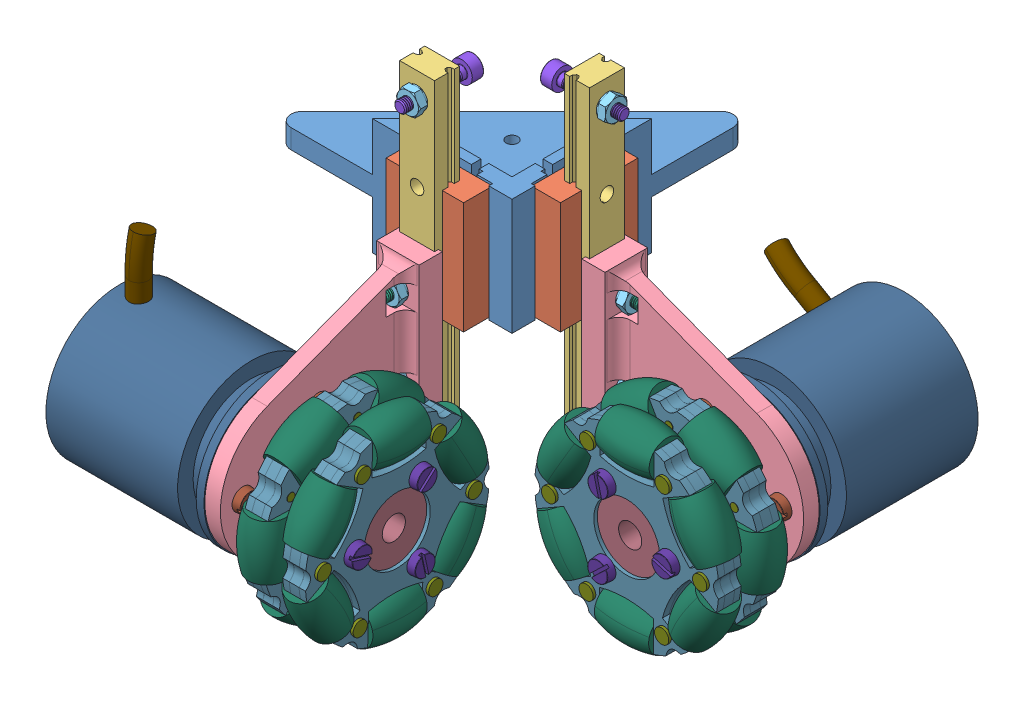
SolidWorks assembly 全场定位, configuration 默认. Lengths in mm.
Overall size (134 104.66 134.28).
113 component instances, 18 part files, 0 mates.
Components (placement in the parent):
- 机架SLDPRT-1: 机架SLDPRT [默认] at (33.577 -2.0729 87.0624) size (60.04 30 60.04)
- 滑块-1: 滑块 [默认] at (40.077 -14.0229 81.0624) x (0 1 0) z (0 0 1) size (28.9 7.5 20)
- 滑块-2: 滑块 [默认] at (7.577 -14.0229 93.5624) x (0 1 0) z (-1 0 0) size (28.9 7.5 20)
- 滑轨-1: 滑轨 [默认] at (17.577 -49.5817 95.5624) size (9 90 6.5)
- 滑轨-2: 滑轨 [默认] at (42.077 -51.1888 71.0624) x (0 0 -1) z (1 0 0) size (9 90 6.5)
- 连接片-1: 连接片 [默认] at (19.577 -30.8137 129.5624) x (0 0 1) z (0 -1 0) size (53.77 11 52.42)
- 连接片-2: 连接片 [默认] at (76.077 -32.4209 69.0624) x (1 0 0) z (0 -1 0) size (53.77 11 52.42)
- hex nut style 1 gradeab_iso_ISO - 4032 - M3 - W - N-1: hex nut style 1 gradeab_iso_ISO - 4032 - M3 - W - N [默认] at (17.577 -45.5817 102.9624) x (-0.883653 0.468143 0) z (0 0 1) size (5.5 6.35 2.4)
- socket head cap screw_iso_ISO 4762 M3 x 12 - 12S-1: socket head cap screw_iso_ISO 4762 M3 x 12 - 12S [默认] at (17.577 -25.5817 89.5624) x (0 0 1) z (0.159835 -0.987144 0) size (15 5.5 5.5)
- socket head cap screw_iso_ISO 4762 M3 x 12 - 12S-2: socket head cap screw_iso_ISO 4762 M3 x 12 - 12S [默认] at (17.577 -5.5817 89.5624) x (0 0 1) z (0.284229 -0.958757 0) size (15 5.5 5.5)
- socket head cap screw_iso_ISO 4762 M3 x 12 - 12S-3: socket head cap screw_iso_ISO 4762 M3 x 12 - 12S [默认] at (36.077 -27.1888 71.0624) x (1 0 0) z (0 -0.834413 -0.551139) size (15 5.5 5.5)
- socket head cap screw_iso_ISO 4762 M3 x 12 - 12S-4: socket head cap screw_iso_ISO 4762 M3 x 12 - 12S [默认] at (36.077 -7.1888 71.0624) x (1 0 0) z (0 -0.855064 -0.518522) size (15 5.5 5.5)
- hex nut style 1 gradeab_iso_ISO - 4032 - M3 - W - N-2: hex nut style 1 gradeab_iso_ISO - 4032 - M3 - W - N [默认] at (17.577 -25.5817 102.9624) x (0 -1 0) z (0 0 1) size (5.5 6.35 2.4)
- hex nut style 1 gradeab_iso_ISO - 4032 - M3 - W - N-3: hex nut style 1 gradeab_iso_ISO - 4032 - M3 - W - N [默认] at (17.577 -5.5817 102.9624) x (0 -1 0) z (0 0 1) size (5.5 6.35 2.4)
- hex nut style 1 gradeab_iso_ISO - 4032 - M3 - W - N-4: hex nut style 1 gradeab_iso_ISO - 4032 - M3 - W - N [默认] at (49.477 -7.1888 71.0624) x (0 0.5 -0.866025) z (1 0 0) size (5.5 6.35 2.4)
- hex nut style 1 gradeab_iso_ISO - 4032 - M3 - W - N-5: hex nut style 1 gradeab_iso_ISO - 4032 - M3 - W - N [默认] at (49.477 -27.1888 71.0624) x (0 0.5 -0.866025) z (1 0 0) size (5.5 6.35 2.4)
- hex nut style 1 gradeab_iso_ISO - 4032 - M3 - W - N-6: hex nut style 1 gradeab_iso_ISO - 4032 - M3 - W - N [默认] at (49.477 -47.1888 71.0624) x (0 0.5 -0.866025) z (1 0 0) size (5.5 6.35 2.4)
- socket set screw cone point_iso_ISO 4027 - M4 x 4-N-1: socket set screw cone point_iso_ISO 4027 - M4 x 4-N [默认] at (27.077 -24.3164 129.375) x (0 -0.999584 0.028835) z (0.266634 -0.027791 -0.963397) size (4 4 4)
- socket set screw cone point_iso_ISO 4027 - M4 x 4-N-2: socket set screw cone point_iso_ISO 4027 - M4 x 4-N [默认] at (70.4593 -29.151 80.5624) x (0.864249 -0.503064 0) z (0.099801 0.171456 -0.980124) size (4 4 4)
- socket head cap screw_iso_ISO 4762 M3 x 16 - 16S-1: socket head cap screw_iso_ISO 4762 M3 x 16 - 16S [默认] at (32.577 -47.1888 71.0624) x (1 0 0) z (0 -0.325683 0.945479) size (19 5.5 5.5)
- hex nut style 1 gradeab_iso_ISO - 4032 - M3 - W - N-7: hex nut style 1 gradeab_iso_ISO - 4032 - M3 - W - N [默认] at (36.677 -47.1888 71.0624) x (0 -0.95795 0.286936) z (-1 0 0) size (5.5 6.35 2.4)
- hex nut style 1 gradeab_iso_ISO - 4032 - M3 - W - N-8: hex nut style 1 gradeab_iso_ISO - 4032 - M3 - W - N [默认] at (17.577 -45.5817 90.1624) x (-0.5 0.866025 0) z (0 0 -1) size (5.5 6.35 2.4)
- socket head cap screw_iso_ISO 4762 M3 x 16 - 16S-2: socket head cap screw_iso_ISO 4762 M3 x 16 - 16S [默认] at (17.577 -45.5817 86.0624) x (0 0 1) z (-0.77707 -0.629414 0) size (19 5.5 5.5)
- socket head cap screw_iso_ISO 4762 M3 x 6 - 6S-1: socket head cap screw_iso_ISO 4762 M3 x 6 - 6S [默认] at (23.577 5.4271 63.5624) x (1 0 0) z (0 0.484775 0.874639) size (9 5.5 5.5)
- socket head cap screw_iso_ISO 4762 M3 x 6 - 6S-2: socket head cap screw_iso_ISO 4762 M3 x 6 - 6S [默认] at (25.577 5.4271 78.5624) x (1 0 0) z (0 0.339966 0.940438) size (9 5.5 5.5)
- socket head cap screw_iso_ISO 4762 M3 x 6 - 6S-3: socket head cap screw_iso_ISO 4762 M3 x 6 - 6S [默认] at (25.577 -4.5729 63.5624) x (1 0 0) z (0 0.125522 0.992091) size (9 5.5 5.5)
- socket head cap screw_iso_ISO 4762 M3 x 6 - 6S-4: socket head cap screw_iso_ISO 4762 M3 x 6 - 6S [默认] at (10.077 5.4271 77.0624) x (0 0 1) z (-0.629289 -0.777171 0) size (9 5.5 5.5)
- socket head cap screw_iso_ISO 4762 M3 x 6 - 6S-5: socket head cap screw_iso_ISO 4762 M3 x 6 - 6S [默认] at (10.077 -4.5729 79.0624) x (0 0 1) z (-0.32553 -0.945532 0) size (9 5.5 5.5)
- socket head cap screw_iso_ISO 4762 M3 x 6 - 6S-6: socket head cap screw_iso_ISO 4762 M3 x 6 - 6S [默认] at (25.077 -4.5729 79.0624) x (0 0 1) z (0.017492 -0.999847 0) size (9 5.5 5.5)
- hex nut style 1 gradeab_iso_ISO - 4032 - M3 - W - N-9: hex nut style 1 gradeab_iso_ISO - 4032 - M3 - W - N [默认] at (17.577 34.4183 97.9624) x (-0.846539 -0.532326 0) z (0 0 1) size (5.5 6.35 2.4)
- hex nut style 1 gradeab_iso_ISO - 4032 - M3 - W - N-10: hex nut style 1 gradeab_iso_ISO - 4032 - M3 - W - N [默认] at (17.577 34.4183 90.1624) x (0.675882 -0.73701 0) z (0 0 -1) size (5.5 6.35 2.4)
- hex nut style 1 gradeab_iso_ISO - 4032 - M3 - W - N-11: hex nut style 1 gradeab_iso_ISO - 4032 - M3 - W - N [默认] at (36.677 32.8112 71.0624) x (0 -0.87174 0.489968) z (-1 0 0) size (5.5 6.35 2.4)
- hex nut style 1 gradeab_iso_ISO - 4032 - M3 - W - N-12: hex nut style 1 gradeab_iso_ISO - 4032 - M3 - W - N [默认] at (44.477 32.8112 71.0624) x (0 0.818224 -0.574899) z (1 0 0) size (5.5 6.35 2.4)
- socket head cap screw_iso_ISO 4762 M3 x 16 - 16S-3: socket head cap screw_iso_ISO 4762 M3 x 16 - 16S [默认] at (17.577 34.4183 81.0624) x (0 0 1) z (-0.514934 -0.85723 0) size (19 5.5 5.5)
- socket head cap screw_iso_ISO 4762 M3 x 16 - 16S-4: socket head cap screw_iso_ISO 4762 M3 x 16 - 16S [默认] at (27.577 32.8112 71.0624) x (1 0 0) z (0 -0.968527 0.248907) size (19 5.5 5.5)
- 编码器1-1: 编码器1 [默认] at (-25.223 -30.8137 129.5624) x (0 0 1) z (0 1 0) size (38 40.8 38)
- 编码器1-2: 编码器1 [默认] at (76.077 -32.4209 28.2624) x (-0.5 -0.866025 0) z (-0.866025 0.5 0) size (38 40.8 38)
- slotted cheese head screw_iso_ISO 1207 - M3 x 8 - 8N-1: slotted cheese head screw_iso_ISO 1207 - M3 x 8 - 8N [默认] at (89.077 -32.4209 75.0624) x (0 0 -1) z (1 0 0) size (10.01 8.61 5.5)
- slotted cheese head screw_iso_ISO 1207 - M3 x 8 - 8N-2: slotted cheese head screw_iso_ISO 1207 - M3 x 8 - 8N [默认] at (69.577 -21.1626 75.0624) x (0 0 -1) z (-0.5 0.866025 0) size (10.01 8.61 5.5)
- slotted cheese head screw_iso_ISO 1207 - M3 x 8 - 8N-3: slotted cheese head screw_iso_ISO 1207 - M3 x 8 - 8N [默认] at (69.577 -43.6792 75.0624) x (0 0 -1) z (-0.5 -0.866025 0) size (10.01 8.61 5.5)
- slotted cheese head screw_iso_ISO 1207 - M3 x 8 - 8N-4: slotted cheese head screw_iso_ISO 1207 - M3 x 8 - 8N [默认] at (21.577 -30.8137 142.5624) x (-1 0 0) z (0 0.285358 -0.958421) size (10.01 8.61 5.5)
- slotted cheese head screw_iso_ISO 1207 - M3 x 8 - 8N-5: slotted cheese head screw_iso_ISO 1207 - M3 x 8 - 8N [默认] at (21.577 -42.0721 123.0624) x (-1 0 0) z (0 0.687338 0.726338) size (10.01 8.61 5.5)
- slotted cheese head screw_iso_ISO 1207 - M3 x 8 - 8N-6: slotted cheese head screw_iso_ISO 1207 - M3 x 8 - 8N [默认] at (21.577 -19.5554 123.0624) x (-1 0 0) z (0 -0.972696 0.232083) size (10.01 8.61 5.5)
- 轴-1: 轴 [默认] at (10.577 -30.8137 129.5624) x (0 0.028835 0.999584) z (0 0.999584 -0.028835) size (6 25 6)
- 轴-2: 轴 [默认] at (76.077 -32.4209 64.0624) x (-0.503064 -0.864249 0) z (-0.864249 0.503064 0) size (6 25 6)
- 法兰（新）-1: 法兰（新） [默认] at (40.577 -30.8137 129.5624) x (0 0.999584 -0.028835) z (0 0.028835 0.999584) size (28 22 28)
- 2mm全向轮片1-1: 2mm全向轮片1 [默认] at (35.577 -30.8137 129.5624) x (0 -0.474821 0.880083) z (-1 0 0) size (47.34 45.39 5.9)
- 从动-1: 从动 [默认] at (27.0518 -30.4732 129.7462) x (0 -0.474821 0.880083) z (-0.964226 0.233294 0.125866) size (14 11.67 11.67)
- 从动-2: 从动 [默认] at (27.0518 -30.8026 129.9492) x (0 -0.999584 0.028835) z (-0.964226 0.007644 0.264972) size (14 11.67 11.67)
- 从动-3: 从动 [默认] at (27.0518 -31.1431 129.7655) x (0 -0.524764 -0.851248) z (-0.964226 -0.225651 0.139106) size (14 11.67 11.67)
- 从动-4: 从动 [默认] at (27.0518 -31.1542 129.3787) x (0 0.474821 -0.880083) z (-0.964226 -0.233294 -0.125866) size (14 11.67 11.67)
- 从动-5: 从动 [默认] at (27.0518 -30.8249 129.1757) x (0 0.999584 -0.028835) z (-0.964226 -0.007644 -0.264972) size (14 11.67 11.67)
- 从动-6: 从动 [默认] at (27.0518 -30.4844 129.3594) x (0 0.524764 0.851248) z (-0.964226 0.225651 -0.139106) size (14 11.67 11.67)
- 2mm全向轮片1-2: 2mm全向轮片1 [默认] at (46.477 -30.8137 129.5624) x (0 -0.851248 0.524764) z (-1 0 0) size (47.34 45.39 5.9)
- 从动-7: 从动 [默认] at (37.9518 -30.6107 129.8918) x (0 -0.851248 0.524764) z (-0.964226 0.139106 0.225651) size (14 11.67 11.67)
- 从动-8: 从动 [默认] at (37.9518 -30.9974 129.903) x (0 -0.880083 -0.474821) z (-0.964226 -0.125866 0.233294) size (14 11.67 11.67)
- 从动-9: 从动 [默认] at (37.9518 -31.2005 129.5736) x (0 -0.028835 -0.999584) z (-0.964226 -0.264972 0.007644) size (14 11.67 11.67)
- 从动-10: 从动 [默认] at (37.9518 -31.0168 129.2331) x (0 0.851248 -0.524764) z (-0.964226 -0.139106 -0.225651) size (14 11.67 11.67)
- 从动-11: 从动 [默认] at (37.9518 -30.63 129.2219) x (0 0.880083 0.474821) z (-0.964226 0.125866 -0.233294) size (14 11.67 11.67)
- 从动-12: 从动 [默认] at (37.9518 -30.427 129.5513) x (0 0.028835 0.999584) z (-0.964226 0.264972 -0.007644) size (14 11.67 11.67)
- thin head rivets gb_GB_CONNECTING_PIECE_RIVET_THR 2X6-1: thin head rivets gb_GB_CONNECTING_PIECE_RIVET_THR 2X6 [默认] at (47.157 -14.2144 119.3296) x (-1 0 0) z (0 -0.996106 -0.088163) size (6.68 3.74 3.74)
- thin head rivets gb_GB_CONNECTING_PIECE_RIVET_THR 2X6-2: thin head rivets gb_GB_CONNECTING_PIECE_RIVET_THR 2X6 [默认] at (47.157 -13.6521 138.8214) x (-1 0 0) z (0 -0.421702 -0.906735) size (6.68 3.74 3.74)
- thin head rivets gb_GB_CONNECTING_PIECE_RIVET_THR 2X6-3: thin head rivets gb_GB_CONNECTING_PIECE_RIVET_THR 2X6 [默认] at (47.157 -30.2515 149.0543) x (-1 0 0) z (0 0.574404 -0.818572) size (6.68 3.74 3.74)
- thin head rivets gb_GB_CONNECTING_PIECE_RIVET_THR 2X6-4: thin head rivets gb_GB_CONNECTING_PIECE_RIVET_THR 2X6 [默认] at (47.157 -47.4131 139.7953) x (-1 0 0) z (0 0.996106 0.088163) size (6.68 3.74 3.74)
- thin head rivets gb_GB_CONNECTING_PIECE_RIVET_THR 2X6-5: thin head rivets gb_GB_CONNECTING_PIECE_RIVET_THR 2X6 [默认] at (47.157 -47.9753 120.3034) x (-1 0 0) z (0 0.421702 0.906735) size (6.68 3.74 3.74)
- thin head rivets gb_GB_CONNECTING_PIECE_RIVET_THR 2X6-6: thin head rivets gb_GB_CONNECTING_PIECE_RIVET_THR 2X6 [默认] at (47.157 -31.376 110.0706) x (-1 0 0) z (0 -0.574404 0.818572) size (6.68 3.74 3.74)
- thin head rivets gb_GB_CONNECTING_PIECE_RIVET_THR 2X6-7: thin head rivets gb_GB_CONNECTING_PIECE_RIVET_THR 2X6 [默认] at (28.997 -50.3056 130.1247) x (1 0 0) z (0 -0.812515 -0.582941) size (6.68 3.74 3.74)
- thin head rivets gb_GB_CONNECTING_PIECE_RIVET_THR 2X6-8: thin head rivets gb_GB_CONNECTING_PIECE_RIVET_THR 2X6 [默认] at (28.997 -41.0466 112.9631) x (1 0 0) z (0 0.098584 -0.995129) size (6.68 3.74 3.74)
- thin head rivets gb_GB_CONNECTING_PIECE_RIVET_THR 2X6-9: thin head rivets gb_GB_CONNECTING_PIECE_RIVET_THR 2X6 [默认] at (28.997 -21.5547 112.4008) x (1 0 0) z (0 0.911099 -0.412188) size (6.68 3.74 3.74)
- thin head rivets gb_GB_CONNECTING_PIECE_RIVET_THR 2X6-10: thin head rivets gb_GB_CONNECTING_PIECE_RIVET_THR 2X6 [默认] at (28.997 -11.3218 129.0002) x (1 0 0) z (0 0.812515 0.582941) size (6.68 3.74 3.74)
- thin head rivets gb_GB_CONNECTING_PIECE_RIVET_THR 2X6-11: thin head rivets gb_GB_CONNECTING_PIECE_RIVET_THR 2X6 [默认] at (28.997 -20.5808 146.1618) x (1 0 0) z (0 -0.098584 0.995129) size (6.68 3.74 3.74)
- thin head rivets gb_GB_CONNECTING_PIECE_RIVET_THR 2X6-12: thin head rivets gb_GB_CONNECTING_PIECE_RIVET_THR 2X6 [默认] at (28.997 -40.0727 146.7241) x (1 0 0) z (0 -0.911099 0.412188) size (6.68 3.74 3.74)
- slotted cheese head screw_iso_ISO 1207 - M3 x 10 - 10N-1: slotted cheese head screw_iso_ISO 1207 - M3 x 10 - 10N [默认] at (27.677 -25.5907 119.8815) x (1 0 0) z (0 0.028835 0.999584) size (12.01 8.61 5.5)
- slotted cheese head screw_iso_ISO 1207 - M3 x 10 - 10N-2: slotted cheese head screw_iso_ISO 1207 - M3 x 10 - 10N [默认] at (27.677 -25.0413 138.9262) x (1 0 0) z (0 -0.880083 -0.474821) size (12.01 8.61 5.5)
- slotted cheese head screw_iso_ISO 1207 - M3 x 10 - 10N-3: slotted cheese head screw_iso_ISO 1207 - M3 x 10 - 10N [默认] at (27.677 -41.8092 129.8796) x (1 0 0) z (0 0.851248 -0.524764) size (12.01 8.61 5.5)
- slotted cheese head screw_iso_ISO 1207 - M3 x 10 - 10N-4: slotted cheese head screw_iso_ISO 1207 - M3 x 10 - 10N [默认] at (48.477 -21.45 123.79) x (-1 0 0) z (0 0.673889 -0.738833) size (12.01 8.61 5.5)
- slotted cheese head screw_iso_ISO 1207 - M3 x 10 - 10N-5: slotted cheese head screw_iso_ISO 1207 - M3 x 10 - 10N [默认] at (48.477 -30.4965 140.5579) x (-1 0 0) z (0 0.302904 0.953021) size (12.01 8.61 5.5)
- slotted cheese head screw_iso_ISO 1207 - M3 x 10 - 10N-6: slotted cheese head screw_iso_ISO 1207 - M3 x 10 - 10N [默认] at (48.477 -40.4946 124.3394) x (-1 0 0) z (0 -0.976792 -0.214188) size (12.01 8.61 5.5)
- 法兰（新）-2: 法兰（新） [默认] at (76.077 -32.4209 94.0624) x (-0.864249 0.503064 0) z (-0.503064 -0.864249 0) size (28 22 28)
- 2mm全向轮片1-3: 2mm全向轮片1 [默认] at (76.077 -32.4209 89.0624) x (-0.003541 -0.999994 0) z (0 0 -1) size (47.34 45.39 5.9)
- 从动-13: 从动 [默认] at (75.69 -32.4195 80.5373) x (-0.003541 -0.999994 0) z (-0.265081 0.000939 -0.964226) size (14 11.67 11.67)
- 从动-14: 从动 [默认] at (75.8823 -32.7553 80.5373) x (0.864249 -0.503064 0) z (-0.133353 -0.229097 -0.964226) size (14 11.67 11.67)
- 从动-15: 从动 [默认] at (76.2692 -32.7566 80.5373) x (0.867791 0.49693 0) z (0.131727 -0.230036 -0.964226) size (14 11.67 11.67)
- 从动-16: 从动 [默认] at (76.4639 -32.4223 80.5373) x (0.003541 0.999994 0) z (0.265081 -0.000939 -0.964226) size (14 11.67 11.67)
- 从动-17: 从动 [默认] at (76.2716 -32.0865 80.5373) x (-0.864249 0.503064 0) z (0.133353 0.229097 -0.964226) size (14 11.67 11.67)
- 从动-18: 从动 [默认] at (75.8847 -32.0851 80.5373) x (-0.867791 -0.49693 0) z (-0.131727 0.230036 -0.964226) size (14 11.67 11.67)
- 2mm全向轮片1-4: 2mm全向轮片1 [默认] at (76.077 -32.4209 99.9624) x (0.49693 -0.867791 0) z (0 0 -1) size (47.34 45.39 5.9)
- 从动-19: 从动 [默认] at (75.7412 -32.6132 91.4373) x (0.49693 -0.867791 0) z (-0.230036 -0.131727 -0.964226) size (14 11.67 11.67)
- 从动-20: 从动 [默认] at (76.0756 -32.8078 91.4373) x (0.999994 -0.003541 0) z (-0.000939 -0.265081 -0.964226) size (14 11.67 11.67)
- 从动-21: 从动 [默认] at (76.4113 -32.6155 91.4373) x (0.503064 0.864249 0) z (0.229097 -0.133353 -0.964226) size (14 11.67 11.67)
- 从动-22: 从动 [默认] at (76.4127 -32.2286 91.4373) x (-0.49693 0.867791 0) z (0.230036 0.131727 -0.964226) size (14 11.67 11.67)
- 从动-23: 从动 [默认] at (76.0783 -32.034 91.4373) x (-0.999994 0.003541 0) z (0.000939 0.265081 -0.964226) size (14 11.67 11.67)
- 从动-24: 从动 [默认] at (75.7426 -32.2262 91.4373) x (-0.503064 -0.864249 0) z (-0.229097 0.133353 -0.964226) size (14 11.67 11.67)
- thin head rivets gb_GB_CONNECTING_PIECE_RIVET_THR 2X6-13: thin head rivets gb_GB_CONNECTING_PIECE_RIVET_THR 2X6 [默认] at (66.3868 -15.499 100.6424) x (0 0 -1) z (0.917111 -0.398631 0) size (6.68 3.74 3.74)
- thin head rivets gb_GB_CONNECTING_PIECE_RIVET_THR 2X6-14: thin head rivets gb_GB_CONNECTING_PIECE_RIVET_THR 2X6 [默认] at (56.5771 -32.3518 100.6424) x (0 0 -1) z (0.80378 0.594926 0) size (6.68 3.74 3.74)
- thin head rivets gb_GB_CONNECTING_PIECE_RIVET_THR 2X6-15: thin head rivets gb_GB_CONNECTING_PIECE_RIVET_THR 2X6 [默认] at (66.2672 -49.2737 100.6424) x (0 0 -1) z (-0.113331 0.993557 0) size (6.68 3.74 3.74)
- thin head rivets gb_GB_CONNECTING_PIECE_RIVET_THR 2X6-16: thin head rivets gb_GB_CONNECTING_PIECE_RIVET_THR 2X6 [默认] at (85.7671 -49.3428 100.6424) x (0 0 -1) z (-0.917111 0.398631 0) size (6.68 3.74 3.74)
- thin head rivets gb_GB_CONNECTING_PIECE_RIVET_THR 2X6-17: thin head rivets gb_GB_CONNECTING_PIECE_RIVET_THR 2X6 [默认] at (95.5768 -32.4899 100.6424) x (0 0 -1) z (-0.80378 -0.594926 0) size (6.68 3.74 3.74)
- thin head rivets gb_GB_CONNECTING_PIECE_RIVET_THR 2X6-18: thin head rivets gb_GB_CONNECTING_PIECE_RIVET_THR 2X6 [默认] at (85.8867 -15.568 100.6424) x (0 0 -1) z (0.113331 -0.993557 0) size (6.68 3.74 3.74)
- thin head rivets gb_GB_CONNECTING_PIECE_RIVET_THR 2X6-19: thin head rivets gb_GB_CONNECTING_PIECE_RIVET_THR 2X6 [默认] at (92.9298 -42.2306 82.4824) x (0 0 1) z (0.992317 0.123724 0) size (6.68 3.74 3.74)
- thin head rivets gb_GB_CONNECTING_PIECE_RIVET_THR 2X6-20: thin head rivets gb_GB_CONNECTING_PIECE_RIVET_THR 2X6 [默认] at (92.9989 -22.7307 82.4824) x (0 0 1) z (0.38901 0.921234 0) size (6.68 3.74 3.74)
- thin head rivets gb_GB_CONNECTING_PIECE_RIVET_THR 2X6-21: thin head rivets gb_GB_CONNECTING_PIECE_RIVET_THR 2X6 [默认] at (76.146 -12.921 82.4824) x (0 0 1) z (-0.603307 0.797509 0) size (6.68 3.74 3.74)
- thin head rivets gb_GB_CONNECTING_PIECE_RIVET_THR 2X6-22: thin head rivets gb_GB_CONNECTING_PIECE_RIVET_THR 2X6 [默认] at (59.2241 -22.6111 82.4824) x (0 0 1) z (-0.992317 -0.123724 0) size (6.68 3.74 3.74)
- thin head rivets gb_GB_CONNECTING_PIECE_RIVET_THR 2X6-23: thin head rivets gb_GB_CONNECTING_PIECE_RIVET_THR 2X6 [默认] at (59.155 -42.111 82.4824) x (0 0 1) z (-0.38901 -0.921234 0) size (6.68 3.74 3.74)
- thin head rivets gb_GB_CONNECTING_PIECE_RIVET_THR 2X6-24: thin head rivets gb_GB_CONNECTING_PIECE_RIVET_THR 2X6 [默认] at (76.0079 -51.9208 82.4824) x (0 0 1) z (0.603307 -0.797509 0) size (6.68 3.74 3.74)
- slotted cheese head screw_iso_ISO 1207 - M3 x 10 - 10N-7: slotted cheese head screw_iso_ISO 1207 - M3 x 10 - 10N [默认] at (76.1159 -21.421 81.1624) x (0 0 1) z (-0.503064 -0.864249 0) size (12.01 8.61 5.5)
- slotted cheese head screw_iso_ISO 1207 - M3 x 10 - 10N-8: slotted cheese head screw_iso_ISO 1207 - M3 x 10 - 10N [默认] at (66.5313 -37.8871 81.1624) x (0 0 1) z (0.999994 -0.003541 0) size (12.01 8.61 5.5)
- slotted cheese head screw_iso_ISO 1207 - M3 x 10 - 10N-9: slotted cheese head screw_iso_ISO 1207 - M3 x 10 - 10N [默认] at (85.5837 -37.9546 81.1624) x (0 0 1) z (-0.49693 0.867791 0) size (12.01 8.61 5.5)
- slotted cheese head screw_iso_ISO 1207 - M3 x 10 - 10N-10: slotted cheese head screw_iso_ISO 1207 - M3 x 10 - 10N [默认] at (70.6107 -22.8752 101.9624) x (0 0 -1) z (-0.238828 0.971062 0) size (12.01 8.61 5.5)
- slotted cheese head screw_iso_ISO 1207 - M3 x 10 - 10N-11: slotted cheese head screw_iso_ISO 1207 - M3 x 10 - 10N [默认] at (70.5433 -41.9276 101.9624) x (0 0 -1) z (-0.721551 -0.692362 0) size (12.01 8.61 5.5)
- slotted cheese head screw_iso_ISO 1207 - M3 x 10 - 10N-12: slotted cheese head screw_iso_ISO 1207 - M3 x 10 - 10N [默认] at (87.0769 -32.4598 101.9624) x (0 0 -1) z (0.960378 -0.2787 0) size (12.01 8.61 5.5)
- 电线-1: 电线 [默认] at (-20.223 -13.8137 129.5624) x (0 1 0) z (0 0 1) size (17.17 5.25 6.09)
- 电线-2: 电线 [默认] at (61.3545 -23.9209 33.2624) x (-0.866025 0.5 0) z (0.046757 0.080985 0.995618) size (17.17 5.25 6.09)
